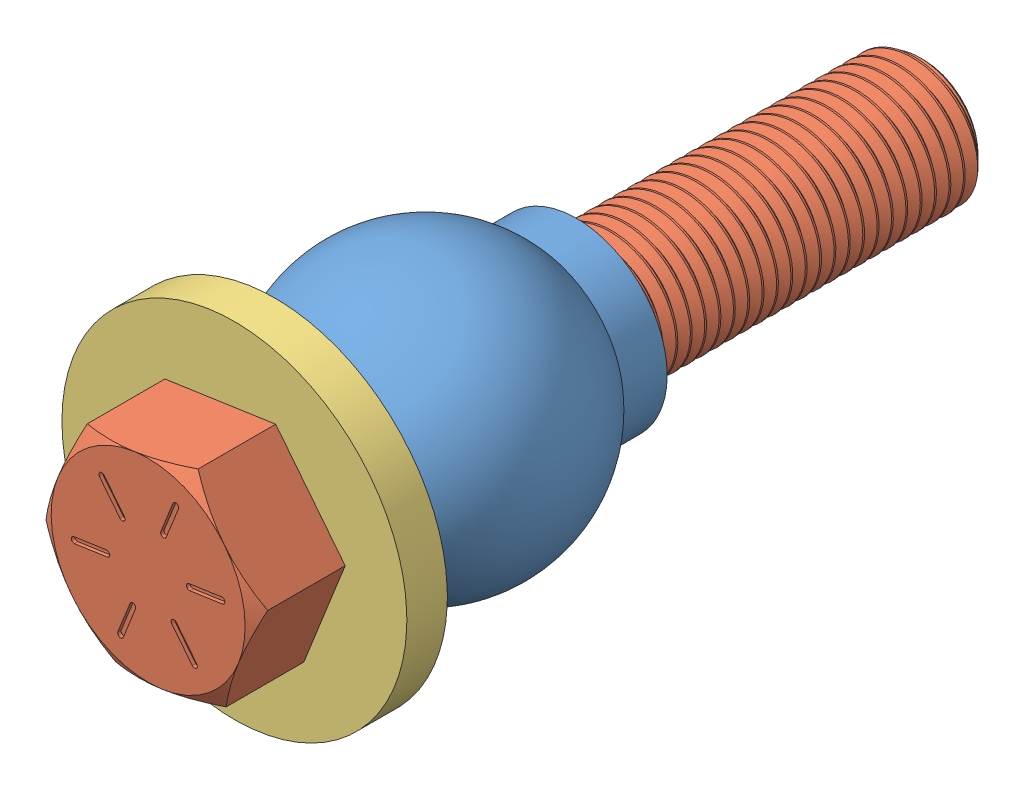
SolidWorks assembly Assem1, configuration Default. Lengths in mm.
Overall size (25.44 25.44 57.6).
3 component instances, 3 part files, 4 mates.
Components (placement in the parent):
- BallSuper-Swivel  Joint Rod End6960T231_-1: BallSuper-Swivel  Joint Rod End6960T231_ [6960T231] at (7.446 -9.6488 19.0007) size (20.64 20.64 22.23)
- 91257A659_Zinc Yellow-Chromate Plated Hex Head Screw-1: 91257A659_Zinc Yellow-Chromate Plated Hex Head Screw [91257A659] at (7.446 9.4012 10.8727) x (0 0 -1) z (0.784306 0.620374 0) size (57.6 16.5 14.29)
- 3-8 98029A046_Black-Oxide Steel Oversized Washer-1: 3-8 98029A046_Black-Oxide Steel Oversized Washer [98029A046] at (7.446 9.4012 31.6055) x (0.999999 -0.001507 0) z (0 0 1) size (25.4 25.4 2.98)
Mates (geometry in assembly coordinates):
- Concentric11: concentric anti-aligned: cylinder of BallSuper-Swivel  Joint Rod End6960T231_-1 through (7.446 9.4012 7.8882) axis (0 0 1) radius 6.6675; cylinder of 91257A659_Zinc Yellow-Chromate Plated Hex Head Screw-1 through (7.446 9.4012 33.0977) axis (0 0 -1) radius 4.7625
- Coincident11: coincident anti-aligned: plane of 3-8 98029A046_Black-Oxide Steel Oversized Washer-1 through (7.446 9.4012 33.0977) normal (0 0 1); plane of 91257A659_Zinc Yellow-Chromate Plated Hex Head Screw-1 through (10.4902 17.0678 33.0977) normal (0 0 -1)
- Concentric2: concentric aligned: circle of BallSuper-Swivel  Joint Rod End6960T231_-1; circle of 3-8 98029A046_Black-Oxide Steel Oversized Washer-1
- Coincident2: coincident anti-aligned: circle of BallSuper-Swivel  Joint Rod End6960T231_-1; plane of 3-8 98029A046_Black-Oxide Steel Oversized Washer-1 through (7.446 9.4012 30.1132) normal (0 0 -1)
